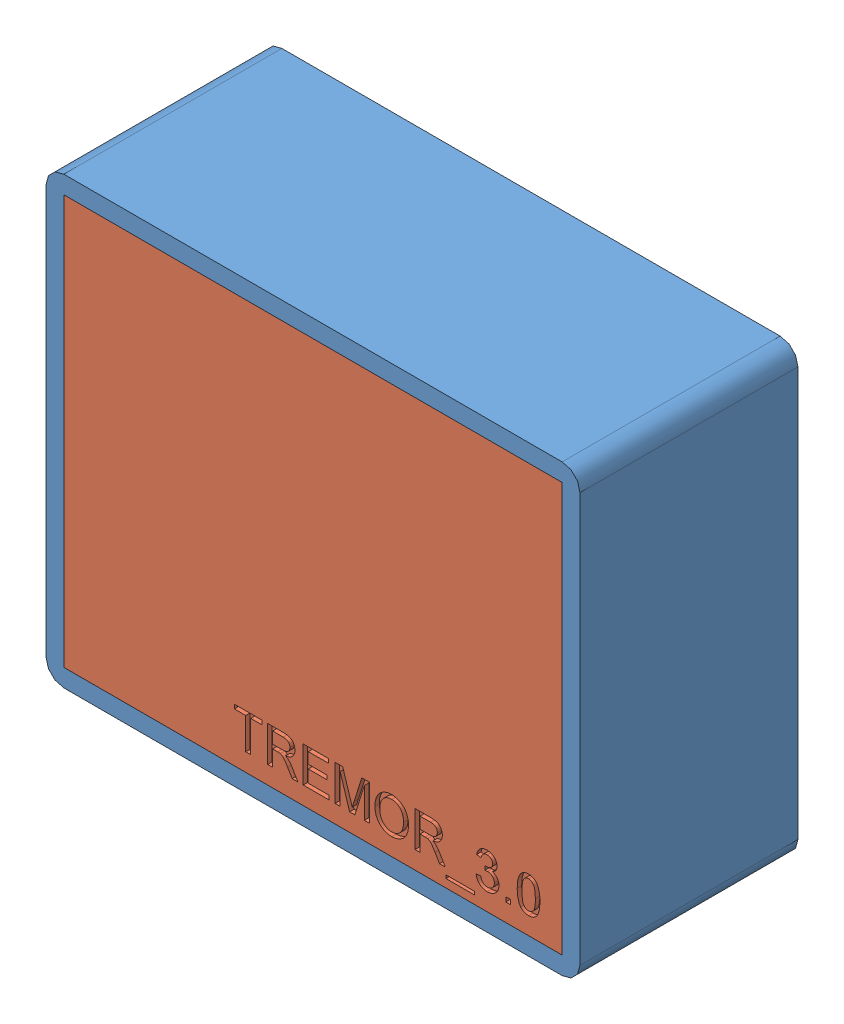
SolidWorks assembly Сборка1, configuration По умолчанию. Lengths in mm.
Overall size (60 50 24.5).
2 component instances, 2 part files, 3 mates.
Components (placement in the parent):
- основание-1: основание [По умолчанию] at (-14.9555 -17.6603 54.3021) size (60 50 24.5)
- Деталь1-2: Деталь1 [По умолчанию] at (-14.9555 -17.6603 76.3021) size (56 46 2.5)
Mates (geometry in assembly coordinates):
- Совпадение8: coincident anti-aligned: plane of основание-1 through (-42.9555 5.3397 76.3021) normal (0 0 1); plane of Деталь1-2 through (-14.9555 -17.6603 76.3021) normal (0 0 -1)
- Совпадение9: coincident anti-aligned: plane of основание-1 through (-32.9555 5.3397 76.3021) normal (0 -1 0); plane of Деталь1-2 through (-42.9555 5.3397 78.8021) normal (0 1 0)
- Совпадение10: coincident anti-aligned: plane of основание-1 through (13.0445 5.3397 76.3021) normal (-1 0 0); plane of Деталь1-2 through (13.0445 5.3397 78.8021) normal (1 0 0)
